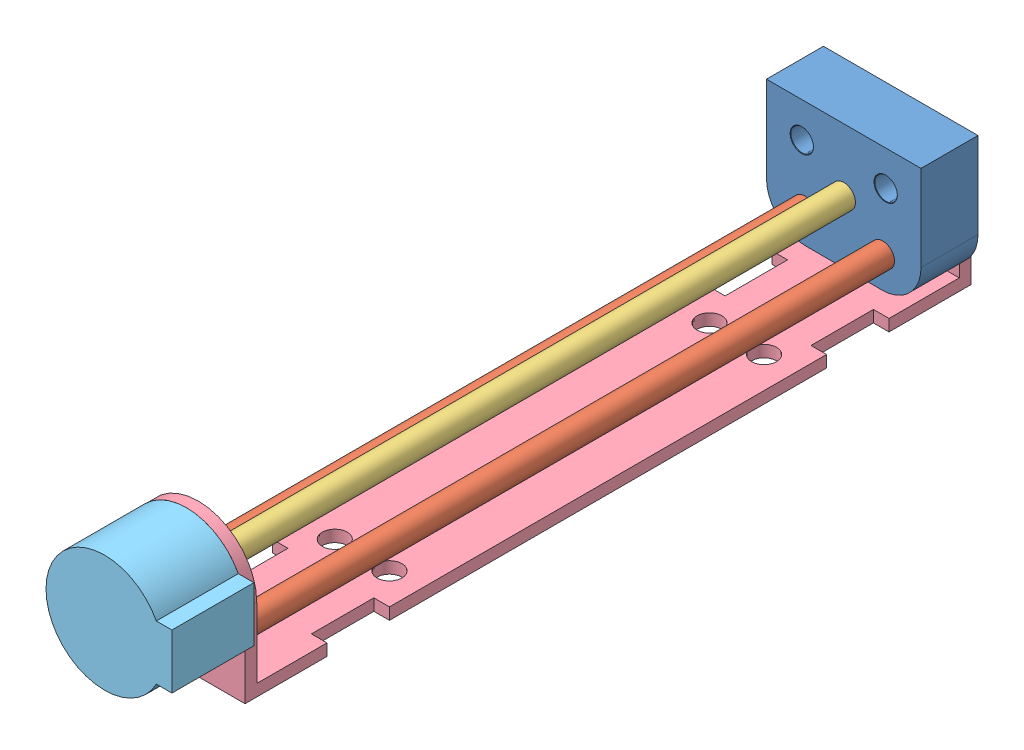
SolidWorks assembly LinearMover, configuration По умолчанию. Lengths in mm.
Overall size (19.8 18.5 103.5).
5 component instances, 5 part files, 10 mates.
Components (placement in the parent):
- Каретка^LinearMover-1: Каретка^LinearMover [По умолчанию] at (0 0 -21.8991) size (19.8 16.77 7.3)
- Направляющие^LinearMover-1: Направляющие^LinearMover [По умолчанию] at (4.9 4 -29.1991) size (13 3 90) (virtual)
- Ось^LinearMover-2: Ось^LinearMover [По умолчанию] at (9.9 8 60.8009) x (0.923728 0.383049 0) z (0 0 -1) size (3 3 90) (virtual)
- Станина^LinearMover-1: Станина^LinearMover [По умолчанию] at (2.4 -2.5 -29.1991) x (0 0 1) z (-1 0 0) size (93 18 15) (virtual)
- Мотор^LinearMover-2: Мотор^LinearMover [По умолчанию] at (9.9 8 62.3009) size (16.13 15 10.5) (virtual)
Mates (geometry in assembly coordinates):
- Концентричный1: concentric: cylinder of Ось^LinearMover-1 through (14.9 4 60.8009) axis (0 0 -1) radius 1.5; cylinder of Каретка^LinearMover-1 through (14.9 4 -29.1991) axis (0 0 1) radius 1.5
- Параллельность2: parallel: cylinder of Каретка^LinearMover-1 through (4.9 4 -29.1991) axis (0 0 1) radius 1.5; cylinder of Ось^LinearMover-1 through (4.9 4 60.8009) axis (0 0 -1) radius 1.5
- Концентричный4: concentric: cylinder of Каретка^LinearMover-1 through (4.9 4 -29.1991) axis (0 0 1) radius 1.5; cylinder of Ось^LinearMover-1 through (4.9 4 60.8009) axis (0 0 -1) radius 1.5
- Совпадение4: coincident: plane of Направляющие^LinearMover-1 through (4.9 4 60.8009) normal (0 0 1); circle of Ось^LinearMover-2
- Концентричный5: concentric: line of assembly; cylinder of assembly; axis of Каретка^LinearMover-1 through (9.9 8 -29.1991) axis (0 0 1); cylinder of Ось^LinearMover-2 through (9.9 8 -29.1991) axis (0 0 1) radius 1.5
- Концентричный6: concentric: line of assembly; cylinder of assembly; axis of Ось^LinearMover-2 through (9.9 8 -29.1991) axis (0 0 1); cylinder of Станина^LinearMover-1 through (9.9 8 62.3009) axis (0 0 -1) radius 1.5
- Совпадение5: coincident: plane of Ось^LinearMover-2 through (9.9 8 60.8009) normal (0 0 1); plane of Станина^LinearMover-1 through (9.9 4.4 60.8009) normal (0 0 -1)
- Концентричный7: concentric: cylinder of Направляющие^LinearMover-1 through (14.9 4 60.8009) axis (0 0 -1) radius 1.5; cylinder of Станина^LinearMover-1 through (14.9 4 62.3009) axis (0 0 -1) radius 1.5
- Концентричный9: concentric: point of Ось^LinearMover-2; cylinder of Мотор^LinearMover-2 through (9.9 8 72.8009) axis (0 0 -1) radius 7.5
- Совпадение12: coincident: plane of Станина^LinearMover-1 through (2.4 -2.5 62.3009) normal (0 0 1); plane of Мотор^LinearMover-2 through (9.9 8 62.3009) normal (0 0 -1)
